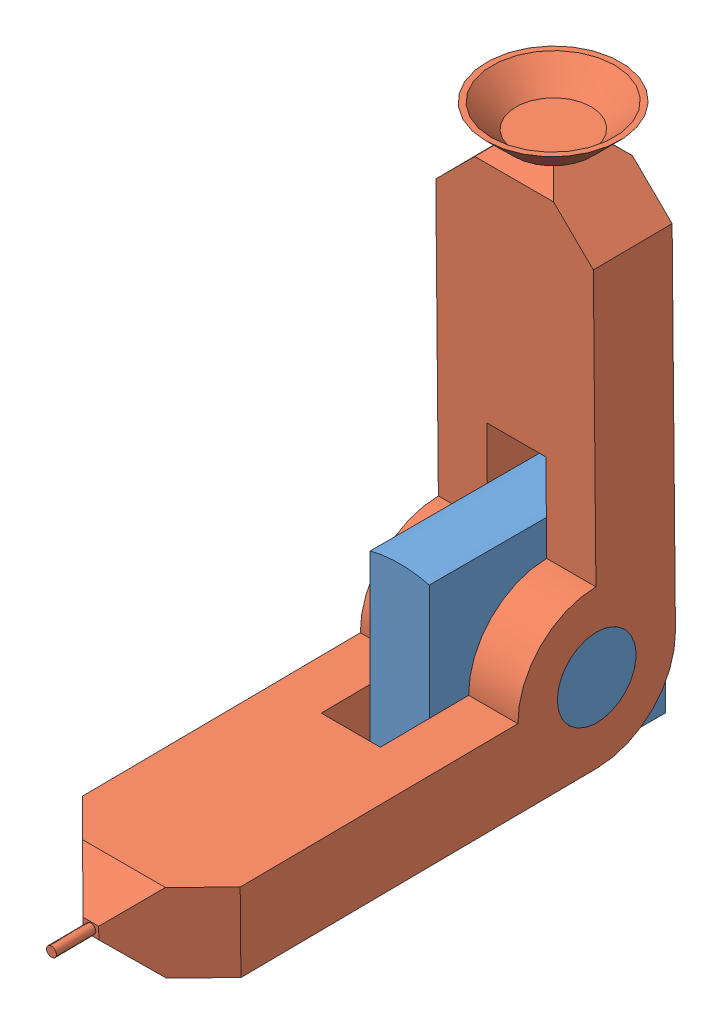
SolidWorks assembly tool_assembly, configuration Default. Lengths in mm.
Overall size (40 142.32 149.54).
2 component instances, 2 part files, 4 mates.
Components (placement in the parent):
- tool_base-1: tool_base [Default] at origin size (40 60 60)
- tool_tip-1: tool_tip [Default] at (0 0 30) x (1 0 0) z (0 -0.009356 0.999956) size (40 132.07 145.57)
Mates (geometry in assembly coordinates):
- Width2: width anti-aligned: plane of tool_base-1 through (-7.5 29.0474 60) normal (-1 0 0); plane of tool_tip-1 through (7.5 29.0474 60) normal (1 0 0); plane of tool_base-1 through (-7.5 0 30) normal (1 0 0); plane of tool_tip-1 through (7.5 0 30) normal (-1 0 0)
- Concentric1: concentric aligned: cylinder of tool_base-1 through (20 0 30) axis (-1 0 0) radius 10; cylinder of tool_tip-1 through (20 0 30) axis (-1 0 0) radius 10
- Concentric2: concentric aligned: cylinder of tool_base-1 through (20 0 30) axis (-1 0 0) radius 10; cylinder of tool_tip-1 through (20 0 30) axis (-1 0 0) radius 10
- Coincident1: coordinate: unknown of tool_base-1
